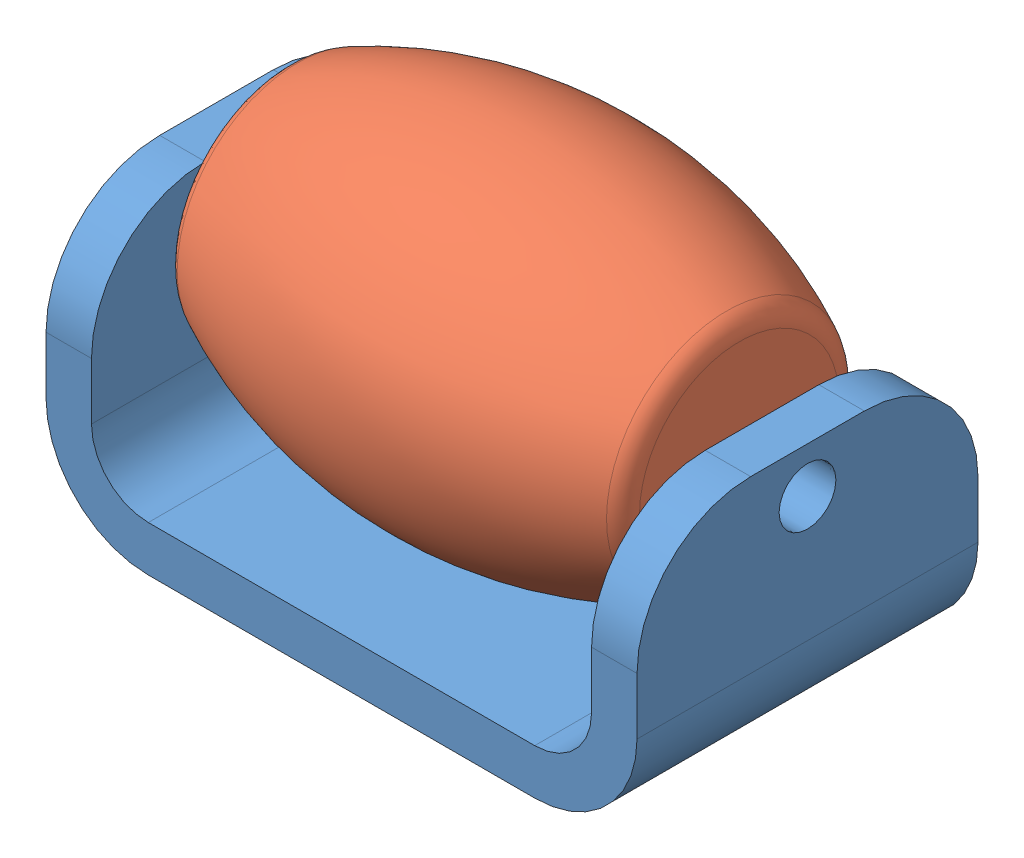
SolidWorks assembly Assem1, configuration Default. Lengths in mm.
Overall size (100 53.28 53.28).
2 component instances, 2 part files, 3 mates.
Components (placement in the parent):
- bracket-1: bracket [Default] at origin size (66.04 30.48 38.1)
- roller-1: roller [Default] at (0 20.32 0) x (1 0 0) z (0 0.804787 0.593563) size (50.8 38.1 38.1)
Mates (geometry in assembly coordinates):
- Coincident1: coordinate: point of bracket-1; point of assembly
- Concentric1: concentric aligned: cylinder of bracket-1 through (0 20.32 0) axis (1 0 0) radius 3.175; line of roller-1 through (10 0 20.32) axis (0 1 0)
- Coincident3: coincident aligned: plane of roller-1; plane of assembly through (0 0 0) normal (1 0 0)
